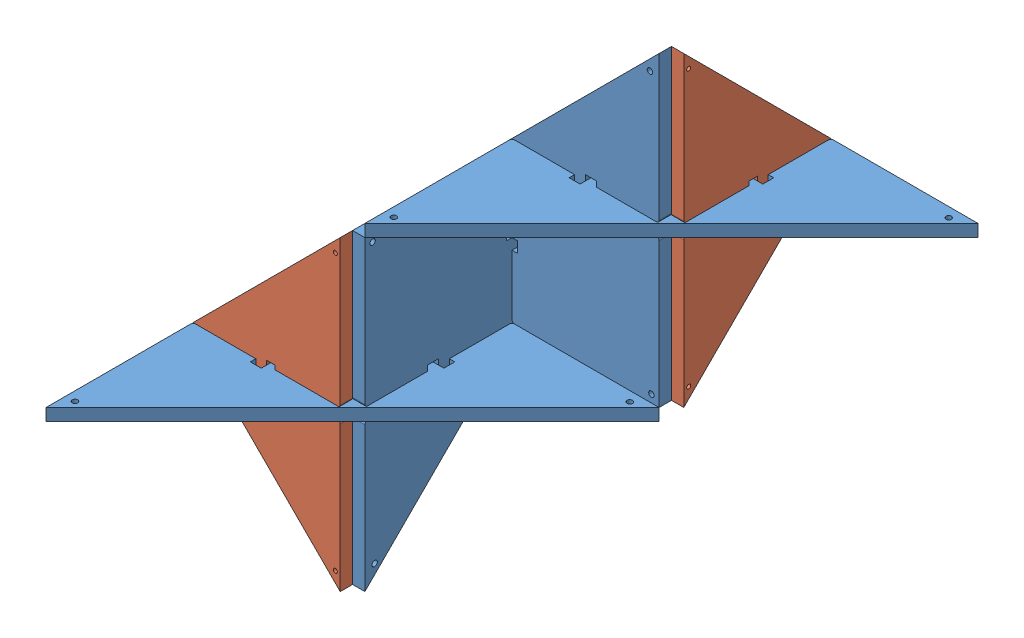
SolidWorks assembly prew, configuration Default. Lengths in mm.
Overall size (684.05 684.05 684.05).
6 component instances, 2 part files, 9 mates.
Components (placement in the parent):
- aglebig-1: aglebig [angle_small] at (400.8703 112.3086 404.5636) x (0 1 0) z (1 0 0) size (450 18.1 450)
- aglebig-2: aglebig [angle_small] at (251.8214 296.8613 220.0109) x (0 0 1) z (-1 0 0) size (450 18.1 450)
- angle_small-2: angle_small [Default] at (452.4209 272.3086 371.113) x (0 1 0) z (0 0 1) size (450 18.1 215.95)
- aglebig-4: aglebig [angle_small] at (218.3709 263.4107 607.2162) x (0 0 -1) z (0 1 0) size (450 18.1 450)
- aglebig-5: aglebig [angle_small] at (17.7714 62.8113 454.0609) x (0 0 1) z (-1 0 0) size (450 18.1 450)
- angle_small-3: angle_small [Default] at (166.8203 38.2586 638.6136) x (0 1 0) z (1 0 0) size (450 18.1 215.95)
Mates (geometry in assembly coordinates):
- Coincident1: coincident anti-aligned: plane of aglebig-2 through (251.8214 314.9613 296.5886) normal (0 0 -1); plane of angle_small-2 through (434.3209 314.9613 296.5886) normal (0 0 1)
- Coincident2: coincident anti-aligned: plane of aglebig-1 through (326.3459 112.3086 422.6636) normal (1 0 0); plane of aglebig-2 through (326.3459 314.9613 220.0109) normal (-1 0 0)
- Coincident3: coincident anti-aligned: line of aglebig-1 through (342.3459 314.9613 422.6636) axis (1 0 0); line of aglebig-2 through (310.3459 314.9613 422.6636) axis (-1 0 0)
- Coincident4: coincident anti-aligned: line of aglebig-2 through (218.3709 296.8613 188.6136) axis (0 0 1); line of aglebig-4 through (218.3709 296.8613 400.5636) axis (0 0 -1)
- Coincident5: coincident: point of aglebig-2; point of aglebig-4
- Coincident6: coincident: point of aglebig-4; point of angle_small-3
- Coincident8: coincident: point of aglebig-1; line of aglebig-5 through (-15.6791 80.9113 422.6636) axis (0 0 1)
- Coincident9: coincident: point of aglebig-1; point of aglebig-5
- Coincident10: coincident: point of aglebig-1; point of angle_small-2
